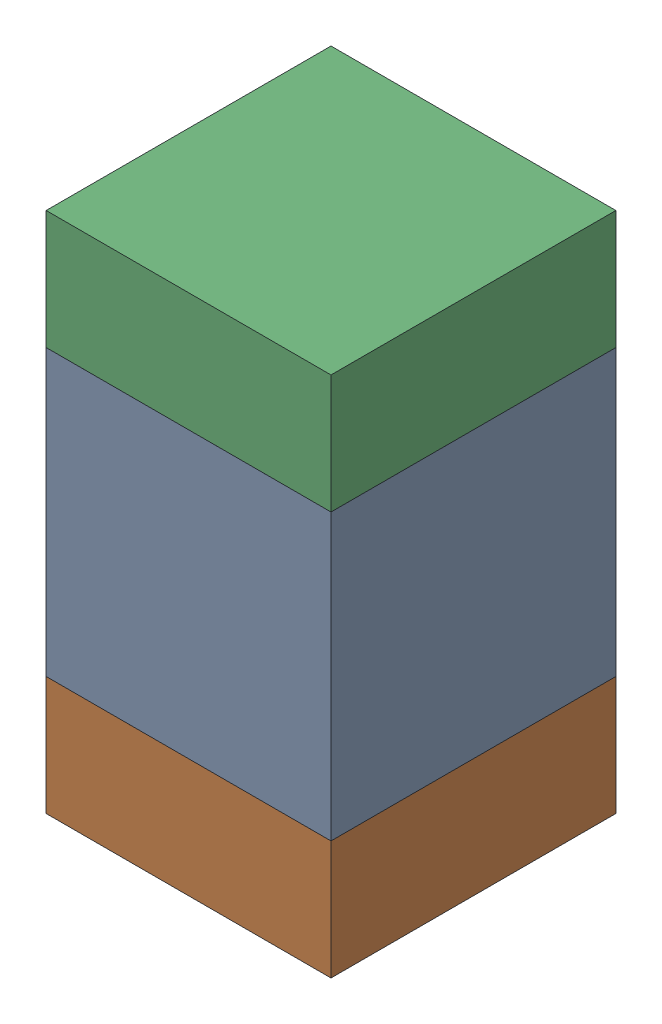
SolidWorks assembly C121_1PCB, configuration Default. Lengths in mm.
Overall size (0.6 1.1 0.6).
6 component instances, 2 part files, 0 mates.
Components (placement in the parent):
- 761606048-1: 761606048 [Default] at (114.1 120.8 0) size (0.6 0.6 0.6)
  - Extruded_9-1: Extruded_9 [Default] at origin size (0.6 0.6 0.6)
- 854785296-1: 854785296 [Default] at (114.1 120.375 0) size (0.6 0.25 0.6)
  - Extruded_10-1: Extruded_10 [Default] at origin size (0.6 0.25 0.6)
- 854785296-2: 854785296 [Default] at (114.1 121.225 0) size (0.6 0.25 0.6)
  - Extruded_10-1: Extruded_10 [Default] at origin size (0.6 0.25 0.6)
